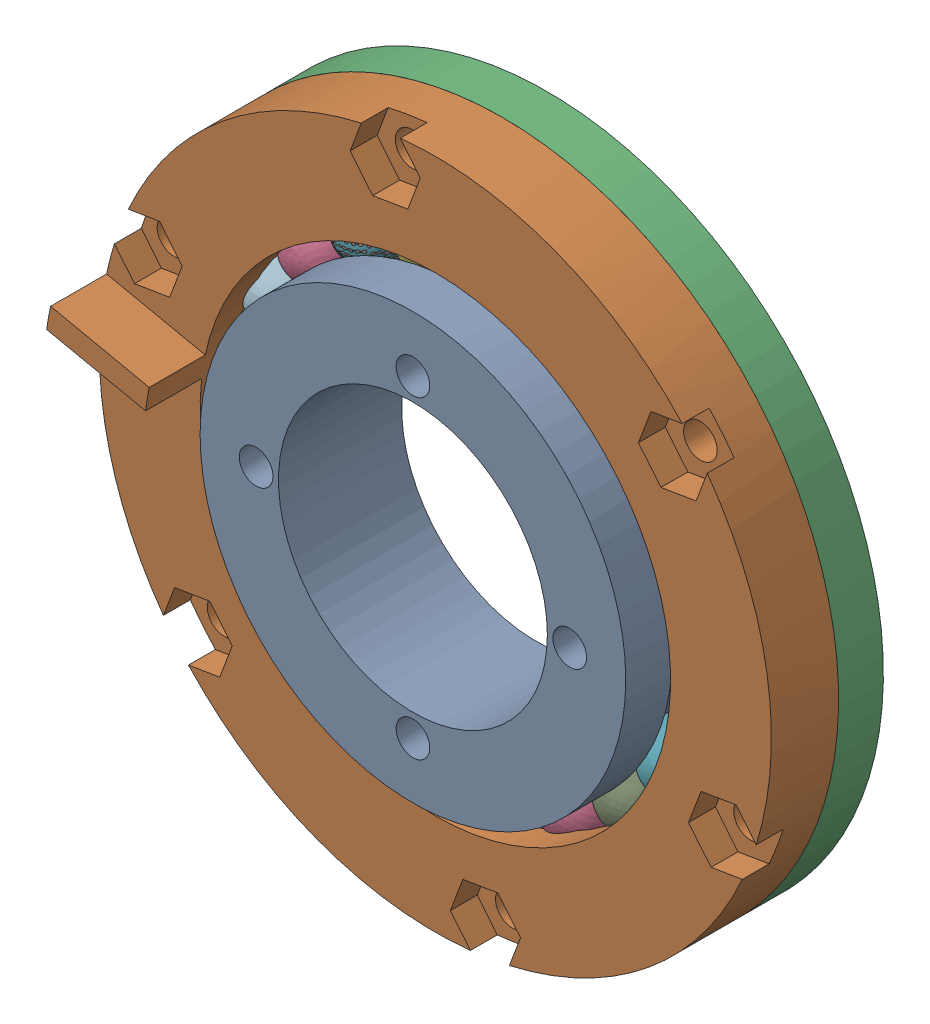
SolidWorks assembly Giunto_rotante, configuration Default. Lengths in mm.
Overall size (77.53 77.39 15.03).
25 component instances, 4 part files, 56 mates.
Components (placement in the parent):
- 1_a-1: 1_a [Default] at origin size (38 38 11)
- 2-1: 2 [Default] at (0 0 9) x (0.93581 -0.352505 0) z (0 0 -1) size (60 60 11)
- 3-1: 3 [Default] at (0 0 -1) x (0.93581 -0.352505 0) z (0 0 1) size (60.25 60 4)
- sfera_6-1: sfera_6 [Default] at (8.0918 -18.29 4) x (0.820888 -0.570937 0.013172) z (-0.103409 -0.125918 0.986636) size (6 6 6)
- sfera_6-2: sfera_6 [Default] at (-9.3574 -17.6759 4) size (6 6 6)
- sfera_6-4: sfera_6 [Default] at (-3.6936 -19.656 4) x (0.823082 -0.206088 -0.52921) z (0.557662 0.116955 0.821787) size (6 6 6)
- sfera_6-5: sfera_6 [Default] at (17.0296 -10.4877 4) x (-0.480643 0.620679 0.619468) z (0.430035 -0.44881 0.783351) size (6 6 6)
- sfera_6-7: sfera_6 [Default] at (2.3027 -19.867 4) x (0.243661 -0.906604 0.344526) z (-0.663302 0.103389 0.741175) size (6 6 6)
- sfera_6-8: sfera_6 [Default] at (13.1525 -15.0669 4) x (0.507413 -0.037006 -0.860908) z (0.860944 -0.020156 0.508301) size (6 6 6)
- sfera_6-15: sfera_6 [Default] at (1.1098 19.9692 4) x (-0.795331 0.033765 0.605235) z (0.312958 0.877961 0.362274) size (6 6 6)
- sfera_6-16: sfera_6 [Default] at (-19.6751 -3.5905 4) x (0.276703 -0.43729 0.855695) z (-0.428303 -0.853245 -0.297539) size (6 6 6)
- sfera_6-17: sfera_6 [Default] at (-18.2473 8.1875 4) x (0.327184 -0.626421 0.707494) z (-0.944646 -0.236149 0.227769) size (6 6 6)
- sfera_6-18: sfera_6 [Default] at (-9.3574 -17.6759 4) x (0.495446 -0.28856 -0.819308) z (0.472129 -0.702265 0.53284) size (6 6 6)
- sfera_6-20: sfera_6 [Default] at (-17.7247 -9.2647 4) x (0.732092 0.013373 0.681075) z (-0.623079 0.417269 0.661558) size (6 6 6)
- sfera_6-21: sfera_6 [Default] at (-14.1791 -14.105 4) size (6 6 6)
- sfera_6-22: sfera_6 [Default] at (-14.9977 13.2313 4) x (-0.480707 0.543965 0.687767) z (-0.455813 -0.825049 0.333958) size (6 6 6)
- sfera_6-23: sfera_6 [Default] at (-19.8547 2.4068 4) x (0.602674 -0.510706 0.613159) z (-0.579809 -0.808184 -0.10325) size (6 6 6)
- sfera_6-25: sfera_6 [Default] at (-4.8631 19.3997 4) x (-0.046893 -0.51825 -0.853943) z (-0.902317 -0.344757 0.258779) size (6 6 6)
- sfera_6-26: sfera_6 [Default] at (-10.3984 17.0843 4) x (-0.787895 -0.44385 0.426871) z (0.583795 -0.758956 0.288392) size (6 6 6)
- sfera_6-27: sfera_6 [Default] at (-10.3984 17.0843 4) x (0.983604 0.179077 0.021312) z (0.063979 -0.236019 -0.96964) size (6 6 6)
- sfera_6-28: sfera_6 [Default] at (6.9828 18.7414 4) x (-0.136113 -0.961086 0.240391) z (0.852935 -0.237118 -0.465056) size (6 6 6)
- sfera_6-32: sfera_6 [Default] at (12.2274 15.8269 4) x (-0.350526 -0.920884 -0.170599) z (0.838901 -0.227739 -0.494348) size (6 6 6)
- sfera_6-33: sfera_6 [Default] at (16.3715 11.488 4) x (-0.136113 -0.961086 0.240391) z (0.852935 -0.237118 -0.465056) size (6 6 6)
- sfera_6-34: sfera_6 [Default] at (19.0422 6.1151 4) x (-0.611862 -0.790635 0.022832) z (0.514928 -0.420076 -0.747252) size (6 6 6)
- sfera_6-35: sfera_6 [Default] at (19.9991 0.1919 4) x (0.947607 0.178675 -0.264795) z (0.271213 -0.88798 0.371397) size (6 6 6)
Mates (geometry in assembly coordinates):
- Coincidente1: coincident aligned: plane of 1-1 through (0 0 0) normal (0 0 1)
- Coincidente2: coincident aligned: plane of 1-1 through (0 0 0) normal (0 1 0)
- Coincidente3: coincident aligned: plane of 1-1 through (0 0 0) normal (1 0 0)
- Tangente1: tangent anti-aligned: torus of 1-1; sphere of sfera_6-1
- Tangente2: tangent anti-aligned: torus of 1-1; sphere of sfera_6-2
- Tangente3: tangent anti-aligned: torus of 1-1; sphere of sfera_6-4
- Tangente4: tangent anti-aligned: torus of 1-1; sphere of sfera_6-8
- Tangente5: tangent anti-aligned: torus of 1-1; sphere of sfera_6-5
- Tangente6: tangent anti-aligned: torus of 1-1; sphere of sfera_6-7
- Distanza1: distance = 0 mm anti-aligned: sphere of sfera_6-5; sphere of sfera_6-8
- Tangente7: tangent anti-aligned: sphere of sfera_6-1; sphere of sfera_6-8
- Tangente8: tangent anti-aligned: sphere of sfera_6-1; sphere of sfera_6-7
- Tangente9: tangent anti-aligned: sphere of sfera_6-4; sphere of sfera_6-7
- Tangente10: tangent anti-aligned: sphere of sfera_6-2; sphere of sfera_6-4
- Tangente15: tangent anti-aligned: torus of 1-1; sphere of sfera_6-15
- Tangente16: tangent anti-aligned: torus of 1-1; sphere of sfera_6-22
- Tangente17: tangent anti-aligned: torus of 1-1; sphere of sfera_6-16
- Tangente18: tangent anti-aligned: torus of 1-1; sphere of sfera_6-18
- Tangente19: tangent anti-aligned: torus of 1-1; sphere of sfera_6-20
- Tangente20: tangent anti-aligned: torus of 1-1; sphere of sfera_6-17
- Tangente21: tangent anti-aligned: torus of 1-1; sphere of sfera_6-21
- Tangente23: tangent anti-aligned: sphere of sfera_6-25; torus of 1-1
- Tangente24: tangent anti-aligned: torus of 1-1; sphere of sfera_6-23
- Tangente25: tangent anti-aligned: torus of 1-1; sphere of sfera_6-26
- Tangente26: tangent anti-aligned: sphere of sfera_6-15; sphere of sfera_6-25
- Tangente27: tangent anti-aligned: sphere of sfera_6-4; sphere of sfera_6-18
- Tangente28: tangent anti-aligned: sphere of sfera_6-18; sphere of sfera_6-21
- Tangente29: tangent anti-aligned: sphere of sfera_6-20; sphere of sfera_6-21
- Tangente30: tangent anti-aligned: sphere of sfera_6-16; sphere of sfera_6-20
- Tangente31: tangent anti-aligned: sphere of sfera_6-16; sphere of sfera_6-23
- Tangente32: tangent anti-aligned: sphere of sfera_6-17; sphere of sfera_6-23
- Tangente33: tangent anti-aligned: sphere of sfera_6-17; sphere of sfera_6-22
- Tangente34: tangent anti-aligned: sphere of sfera_6-22; sphere of sfera_6-26
- Tangente41: tangent anti-aligned: torus of 1-1; sphere of sfera_6-27
- Tangente42: tangent anti-aligned: sphere of sfera_6-25; sphere of sfera_6-27
- Tangente43: tangent anti-aligned: torus of 1-1; sphere of sfera_6-29
- Tangente44: tangent anti-aligned: sphere of sfera_6-27; sphere of sfera_6-29
- Tangente45: tangent anti-aligned: torus of 1-1; sphere of sfera_6-30
- Tangente46: tangent anti-aligned: sphere of sfera_6-29; sphere of sfera_6-30
- Tangente47: tangent anti-aligned: torus of 1-1; sphere of sfera_6-28
- Tangente48: tangent anti-aligned: sphere of sfera_6-28; sphere of sfera_6-30
- Concentrico5: concentric aligned: cylinder of 1-1 through (0 0 11) axis (0 0 -1) radius 12; cylinder of 3-1 through (0 0 3) axis (0 0 -1) radius 21
- Tangente54: tangent anti-aligned: sphere of sfera_6-22; sphere of sfera_6-27
- Tangente55: tangent anti-aligned: torus of 1-1; sphere of sfera_6-32
- Tangente56: tangent anti-aligned: sphere of sfera_6-28; sphere of sfera_6-32
- Tangente57: tangent anti-aligned: sphere of sfera_6-15; sphere of sfera_6-28
- Tangente58: tangent anti-aligned: torus of 1-1; sphere of sfera_6-33
- Tangente59: tangent anti-aligned: sphere of sfera_6-32; sphere of sfera_6-33
- Tangente60: tangent anti-aligned: torus of 1-1; sphere of sfera_6-34
- Tangente61: tangent anti-aligned: sphere of sfera_6-33; sphere of sfera_6-34
- Tangente62: tangent anti-aligned: torus of 1-1; sphere of sfera_6-35
- Tangente63: tangent anti-aligned: sphere of sfera_6-34; sphere of sfera_6-35
- Concentrico7: concentric anti-aligned: cylinder of 1-1 through (0 0 11) axis (0 0 -1) radius 12; cylinder of 2-1 through (0 0 5) axis (0 0 1) radius 21
- Coincidente5: coincident anti-aligned: circle of 2-1; plane of 3-1 through (0 0 3) normal (0 0 1)
- Concentrico8: concentric aligned: cylinder of 3-1 through (25.7348 -9.6939 9) axis (0 0 -1) radius 1.5; cylinder of 2-1 through (25.7348 -9.6939 9) axis (0 0 -1) radius 1.5
- Distanza2: distance = 1 mm aligned: plane of 1-1 through (0 0 0) normal (0 0 -1); plane of 3-1 through (0 0 -1) normal (0 0 -1)
